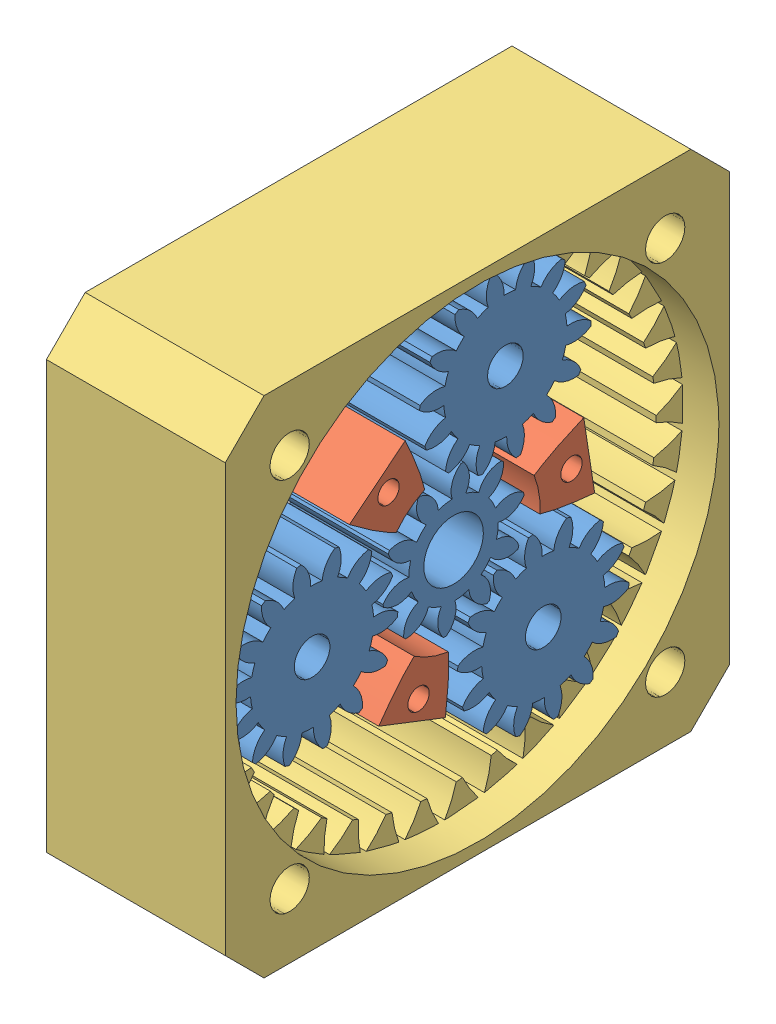
SolidWorks assembly test2, configuration Default. Lengths in mm.
Overall size (15 42.58 42.32).
6 component instances, 3 part files, 13 mates.
Components (placement in the parent):
- spur gear_am-16: spur gear_am [Metric - Spur gear 1M 10T 20PA 10FW ---S10N75H50L5N] at (0 0.4789 -1.0776) x (1 0 0) z (0 0.424329 0.905508) size (10 11.48 12)
- spur gear_am-15: spur gear_am [Metric - Spur gear 0.9M 14T 20PA 10FW ---S14N75H50L3N] at (0 -1.3557 10.7904) x (1 0 0) z (0 0.369418 -0.929263) size (10 14.12 14.4)
- holder-1: holder [Default] at (-3 0.4789 -1.0776) x (0 -0.361827 -0.932245) z (1 0 0) size (30.8 28.01 13.5)
- carrier4-1: carrier4 [Default] at (32.182 -5.3775 -15.6639) size (15 42.3 42.3)
- spur gear_am-14: spur gear_am [Metric - Spur gear 0.9M 14T 20PA 10FW ---S14N75H50L3N] at (0 11.6741 -5.4227) x (1 0 0) z (0 0.498168 0.86708) size (10 14.12 14.4)
- spur gear_am-13: spur gear_am [Metric - Spur gear 0.9M 14T 20PA 10FW ---S14N75H50L3N] at (0 -8.8817 -8.6003) x (1 0 0) z (0 0.989226 0.146398) size (10 14.12 14.4)
Mates (geometry in assembly coordinates):
- Coincident3: coincident: plane of spur gear_am-16 through (0 0.4789 -1.0776) normal (-1 0 0); plane of holder-1 through (0 -1.3557 10.7904) normal (1 0 0)
- Concentric3: concentric: circle of spur gear_am-16; circle of holder-1
- Concentric4: concentric: circle of spur gear_am-15; circle of holder-1
- Concentric5: concentric: circle of spur gear_am-16; circle of carrier4-1
- Coincident7: coincident: plane of holder-1 through (-3 -1.3557 10.7904) normal (-1 0 0); plane of carrier4-1 through (-3 0.4789 -19.0776) normal (-1 0 0)
- Concentric7: concentric: circle of holder-1; circle of spur gear_am-14
- Concentric8: concentric: circle of holder-1; circle of spur gear_am-13
- Coincident8: coincident: plane of holder-1 through (0 -1.3557 10.7904) normal (1 0 0); plane of spur gear_am-13 through (0 -8.8817 -8.6003) normal (-1 0 0)
- Coincident9: coincident: plane of holder-1 through (0 -1.3557 10.7904) normal (1 0 0); plane of spur gear_am-14 through (0 11.6741 -5.4227) normal (-1 0 0)
- GearMate14: gear = 10000 : 14000 mm: circle of spur gear_am-15; circle of spur gear_am-16
- GearMate15: gear = 10000 : 14000 mm: circle of spur gear_am-14; circle of spur gear_am-16
- GearMate16: gear = 10000 : 14000 mm: circle of spur gear_am-13; circle of spur gear_am-16
- GearMate17: gear = 38000 : 14000 mm: circle of spur gear_am-15; circle of carrier4-1
